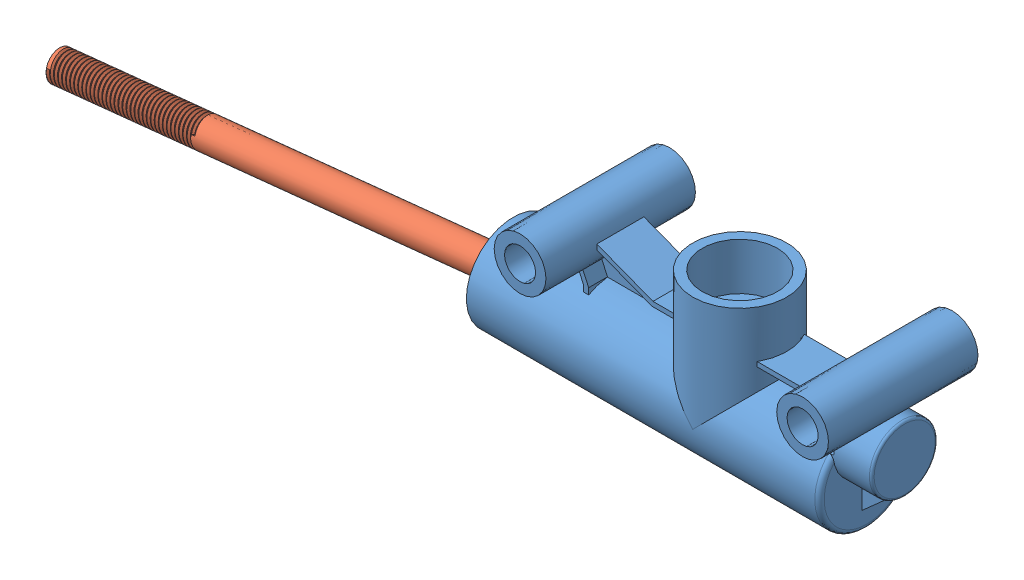
SolidWorks assembly SideMountWilwoodMC, configuration Default. Lengths in mm.
Overall size (224.46 45.29 40.32).
2 component instances, 2 part files, 2 mates.
Components (placement in the parent):
- NewWilwoodMasterCylinder-1: NewWilwoodMasterCylinder [Default] at origin size (105.52 43.57 40.32)
- MCpushrod-1: MCpushrod [Default] at (-75.1401 15.5283 -4.8032) x (0.99655 0.077514 -0.029658) z (-0.003898 -0.313248 -0.949663) size (121.55 7.94 7.94)
Mates (geometry in assembly coordinates):
- Coincident4: coincident: line of NewWilwoodMasterCylinder-1 through (0 28.575 6.35) axis (0 0 1); point of MCpushrod-1
- LimitDistance4: limit distance = 0 mm: plane of assembly; point of MCpushrod-1; plane of NewWilwoodMasterCylinder-1 through (2.54 0 0) normal (-1 0 0)
